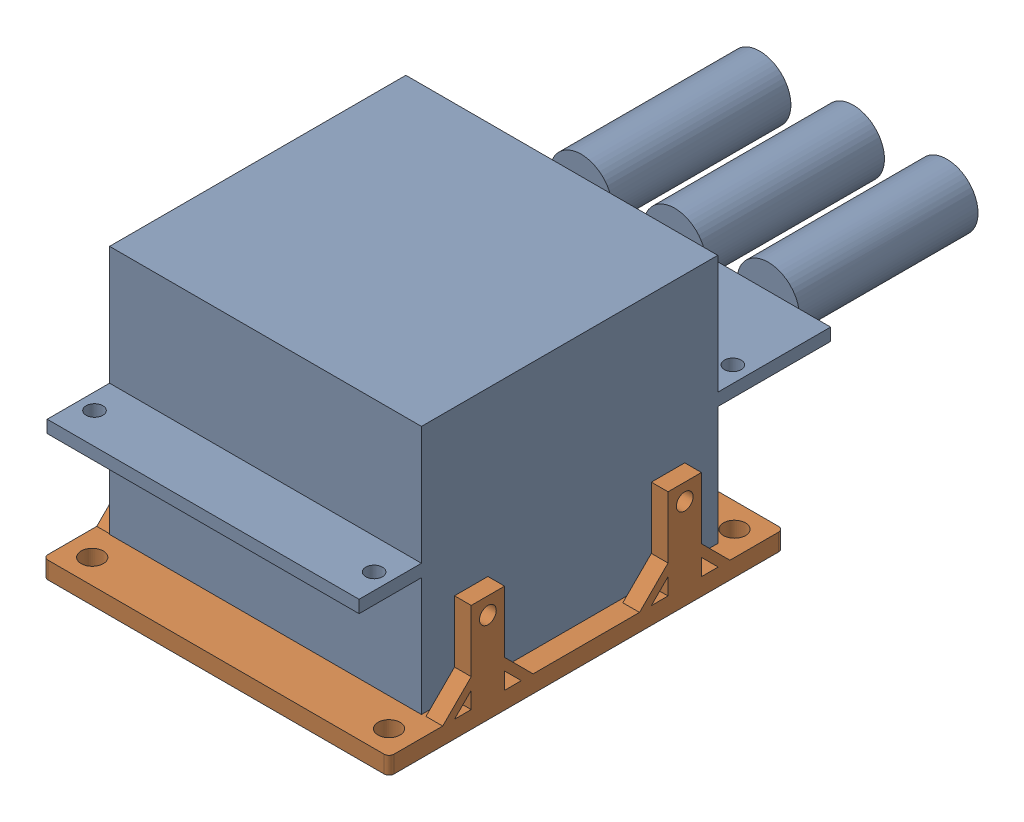
SolidWorks assembly MotorControllerFit, configuration Default. Lengths in mm.
Overall size (70.43 55.09 132.36).
2 component instances, 2 part files, 2 mates.
Components (placement in the parent):
- MotorController-1: MotorController [Default] at (-5.643 11.1095 31.9362) size (63.5 50.8 132.36)
- MotorControllerMount-3: MotorControllerMount [Default] at (-5.7065 -18.5842 -10.9263) size (70.43 21.87 80.32)
Mates (geometry in assembly coordinates):
- Coincident5: coincident aligned: circle of MotorController-1; circle of MotorControllerMount-3
- Parallel2: parallel aligned: plane of MotorController-1 through (26.107 36.5095 -64.0638) normal (0 1 0); plane of MotorControllerMount-3 through (-5.7065 -15.0842 -10.9263) normal (0 1 0)
